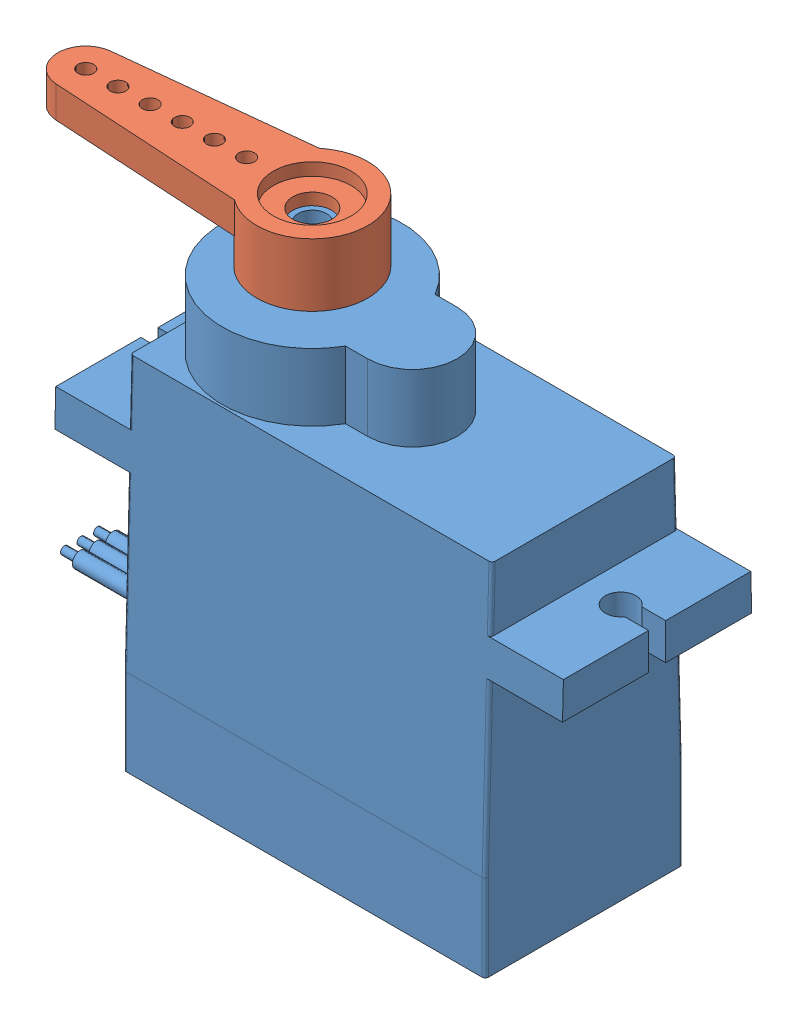
SolidWorks assembly Tower Pro 9g Micro Servo SG90, configuration Default. Lengths in mm.
Overall size (37.89 31.5 12.59).
3 component instances, 3 part files, 4 mates.
Components (placement in the parent):
- Tower Pro 9g Micro Servo SG90-1: Tower Pro 9g Micro Servo SG90 [Default] at origin size (36.67 29.95 12.59)
- SG90 plastic Horn-1: SG90 plastic Horn [Default] at (-1.405 13.16 0) x (-0.999714 0 0.02391) z (-0.02391 0 -0.999714) size (19.4 4 7.07)
- SM-S2309S-Screw-1: SM-S2309S-Screw [Default] at (-1.405 14.36 0) x (0.707107 0 -0.707107) z (0.707107 0 0.707107) (suppressed, hidden)
Mates (geometry in assembly coordinates):
- Coincident4: coincident anti-aligned: plane of SG90 plastic Horn-1 through (-1.2061 14.36 -2.467) normal (0 1 0); plane of SM-S2309S-Screw-1 through (-0.5741 14.36 -0.8309) normal (0 -1 0)
- Concentric1: concentric aligned: cylinder of SG90 plastic Horn-1 through (-1.405 68.16 0) axis (0 1 0) radius 2.375; cylinder of SM-S2309S-Screw-1 through (-1.405 9.16 0) axis (0 1 0) radius 1.175
- Coincident5: coincident anti-aligned: circle of Tower Pro 9g Micro Servo SG90-1; plane of SG90 plastic Horn-1 through (-2.6496 13.61 0.0298) normal (0 -1 0)
- Concentric2: concentric aligned: cylinder of Tower Pro 9g Micro Servo SG90-1 through (-1.405 9.66 0) axis (0 1 0) radius 2.3; cylinder of SG90 plastic Horn-1 through (-1.405 68.16 0) axis (0 1 0) radius 3.535
